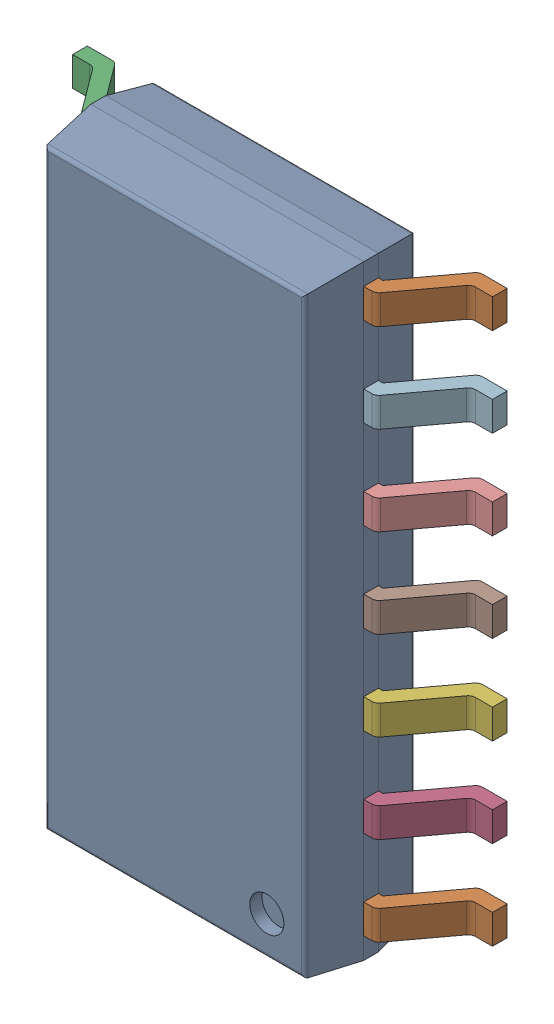
SolidWorks assembly IC11_IC105_1.step, configuration Default. Lengths in mm.
Overall size (6 8.65 1.75).
3 component instances, 2 part files, 0 mates.
Components (placement in the parent):
- 6348793888_1.step-3: 6348793888_1.step [Default] at (343.742 252.954 0) x (-1 0 0) z (0 0 1) size (6 8.65 1.75)
  - Body-16_1.step-14: Body-16_1.step [Default] at origin size (3.9 8.65 1.57)
  - PinsArrayLR-17_1.step-14: PinsArrayLR-17_1.step [Default] at origin size (6 8.04 1)
